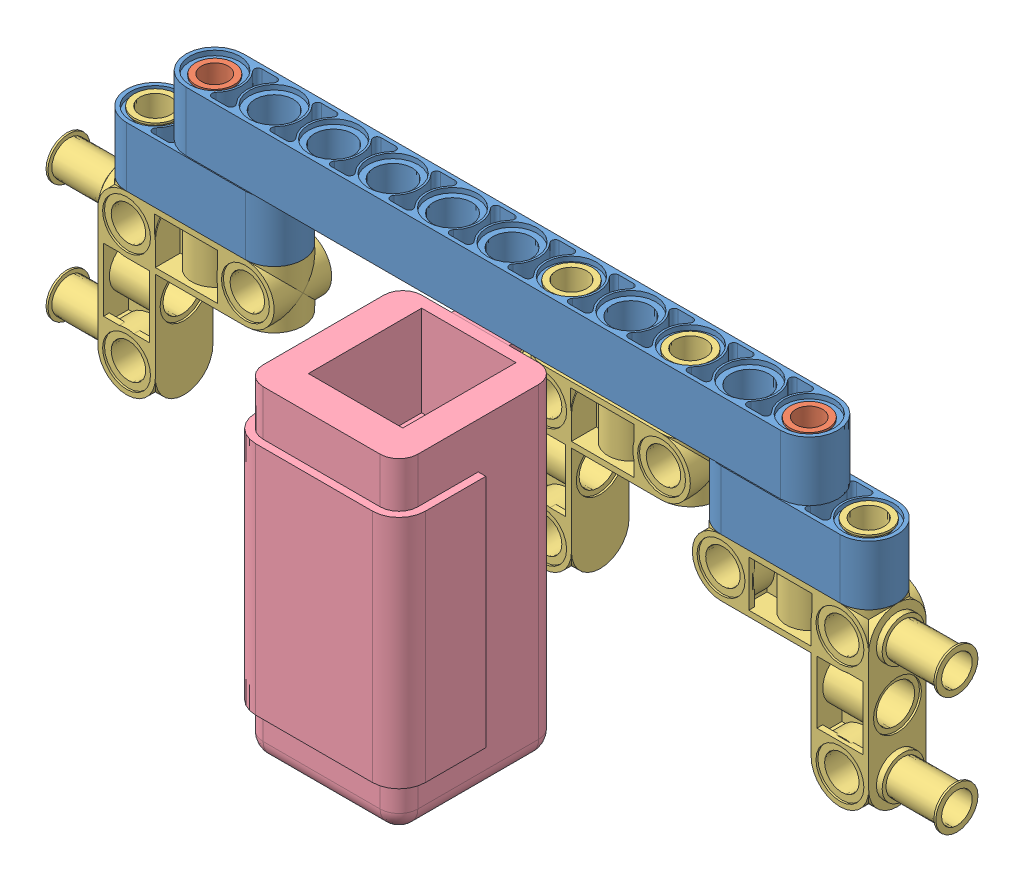
SolidWorks assembly lower_horizontal_connector, configuration Default. Lengths in mm.
Overall size (117.86 51.45 29.62).
9 component instances, 4 part files, 27 mates.
Components (placement in the parent):
- All_Straight-1: All_Straight [Eleven] x (1 0 0) z (0 1 0) size (86.36 7.62 7.87)
- BlueConnectorLong-1: BlueConnectorLong [Default] at (7.874 7.493 0) x (0 -1 0) z (0 0 1) size (22.86 5.59 5.59)
- BlueConnectorLong-2: BlueConnectorLong [Default] at (-70.866 7.493 0) x (0 -1 0) z (0 0 1) size (22.86 5.59 5.59)
- All_Straight-2: All_Straight [Three] at (7.874 -8.001 0) x (1 0 0) z (0 1 0) size (23.37 7.62 7.87)
- All_Straight-3: All_Straight [Three] at (-70.866 -8.001 0) x (1 0 0) z (0 1 0) size (23.37 7.62 7.87)
- Light_Gray_X10-1: Light_Gray_X10 [Default] at (-70.866 -15.621 0) size (31.24 31.24 7.62)
- Light_Gray_X10-3: Light_Gray_X10 [Default] at (7.874 -15.621 0) x (-1 0 0) z (0 0 -1) size (31.24 31.24 7.62)
- Light_Gray_X10-4: Light_Gray_X10 [Default] at (-15.748 -8.001 0) size (31.24 31.24 7.62)
- Light_sensor-1: Light_sensor [Default] at (-31.904 -21.981 14.31) x (-1 0 0) z (0 -1 0) size (22.5 29.62 43.2)
Mates (geometry in assembly coordinates):
- Coincident1: coincident aligned: plane of All_Straight-1 through (0 0 0) normal (0 1 0); plane of assembly through (0 0 0) normal (0 1 0)
- Coincident2: coincident aligned: plane of All_Straight-1; plane of assembly through (0 0 0) normal (1 0 0)
- Coincident3: coincident anti-aligned: plane of All_Straight-1 through (0 0 0) normal (0 0 -1); plane of assembly through (0 0 0) normal (0 0 1)
- Concentric1: concentric anti-aligned: cylinder of All_Straight-1 through (7.874 3.937 0) axis (0 -1 0) radius 2.54; cylinder of BlueConnectorLong-1 through (7.874 7.493 0) axis (0 1 0) radius 2.032
- Coincident4: coincident anti-aligned: plane of All_Straight-1 through (7.874 7.239 0) normal (0 1 0); plane of BlueConnectorLong-1 through (10.414 7.239 0) normal (0 -1 0)
- Parallel1: parallel aligned: plane of BlueConnectorLong-1; plane of assembly through (0 0 0) normal (1 0 0)
- Concentric2: concentric anti-aligned: cylinder of All_Straight-1 through (-70.866 3.937 0) axis (0 -1 0) radius 2.54; cylinder of BlueConnectorLong-2 through (-70.866 7.493 0) axis (0 1 0) radius 2.032
- Coincident5: coincident anti-aligned: plane of All_Straight-1 through (-70.866 7.239 0) normal (0 1 0); plane of BlueConnectorLong-2 through (-68.326 7.239 0) normal (0 -1 0)
- Parallel2: parallel aligned: plane of BlueConnectorLong-2; plane of assembly through (0 0 0) normal (1 0 0)
- Concentric3: concentric anti-aligned: cylinder of BlueConnectorLong-1 through (7.874 7.493 0) axis (0 1 0) radius 2.032; cylinder of All_Straight-2 through (7.874 -4.064 0) axis (0 -1 0) radius 2.54
- Coincident6: coincident anti-aligned: plane of BlueConnectorLong-1 through (9.906 -0.762 0) normal (0 -1 0); plane of All_Straight-2 through (7.874 -0.762 0) normal (0 1 0)
- Parallel3: parallel aligned: plane of All_Straight-1 through (0 3.937 3.81) normal (0 0 1); plane of All_Straight-2 through (7.874 -4.064 3.81) normal (0 0 1)
- Concentric4: concentric anti-aligned: cylinder of BlueConnectorLong-2 through (-70.866 7.493 0) axis (0 1 0) radius 2.032; cylinder of All_Straight-3 through (-70.866 -4.064 0) axis (0 -1 0) radius 2.54
- Coincident7: coincident anti-aligned: plane of BlueConnectorLong-2 through (-68.834 -0.762 0) normal (0 -1 0); plane of All_Straight-3 through (-70.866 -0.762 0) normal (0 1 0)
- Parallel4: parallel aligned: plane of All_Straight-1 through (0 3.937 3.81) normal (0 0 1); plane of All_Straight-3 through (-70.866 -4.064 3.81) normal (0 0 1)
- Concentric5: concentric aligned: cylinder of All_Straight-3 through (-62.992 -4.064 0) axis (0 -1 0) radius 2.54; cylinder of Light_Gray_X10-1 through (-62.992 -0.127 0) axis (0 -1 0) radius 2.286
- Concentric6: concentric aligned: cylinder of All_Straight-3 through (-78.74 -4.064 0) axis (0 -1 0) radius 2.54; cylinder of Light_Gray_X10-1 through (-78.74 -0.127 0) axis (0 -1 0) radius 2.286
- Concentric9: concentric aligned: cylinder of All_Straight-2 through (15.748 -4.064 0) axis (0 -1 0) radius 2.54; cylinder of Light_Gray_X10-3 through (15.748 -0.127 0) axis (0 -1 0) radius 2.286
- Concentric10: concentric aligned: cylinder of All_Straight-2 through (0 -4.064 0) axis (0 -1 0) radius 2.54; cylinder of Light_Gray_X10-3 through (0 -0.127 0) axis (0 -1 0) radius 2.286
- Coincident13: coincident aligned: plane of BlueConnectorLong-2 through (-68.326 -15.367 0) normal (0 -1 0); plane of Light_Gray_X10-1 through (-70.866 -15.367 0) normal (0 -1 0)
- Coincident14: coincident aligned: plane of BlueConnectorLong-1 through (10.414 -15.367 0) normal (0 -1 0); plane of Light_Gray_X10-3 through (7.874 -15.367 0) normal (0 -1 0)
- Concentric11: concentric aligned: cylinder of All_Straight-1 through (-23.622 3.937 0) axis (0 -1 0) radius 2.54; cylinder of Light_Gray_X10-4 through (-23.622 7.493 0) axis (0 -1 0) radius 2.286
- Concentric12: concentric aligned: cylinder of All_Straight-1 through (-7.874 3.937 0) axis (0 -1 0) radius 2.54; cylinder of Light_Gray_X10-4 through (-7.874 7.493 0) axis (0 -1 0) radius 2.286
- Coincident15: coincident anti-aligned: plane of All_Straight-1 through (-15.748 7.239 0) normal (0 1 0); plane of Light_Gray_X10-4 through (-23.622 7.239 0) normal (0 -1 0)
- Concentric13: concentric aligned: cylinder of Light_Gray_X10-4 through (-35.306 -4.191 0) axis (1 0 0) radius 2.286; cylinder of Light_sensor-1 through (-31.877 -4.191 0) axis (1 0 0) radius 2.54
- Concentric14: concentric aligned: cylinder of Light_Gray_X10-4 through (-35.306 -19.939 0) axis (1 0 0) radius 2.286; cylinder of Light_sensor-1 through (-31.877 -19.939 0) axis (1 0 0) radius 2.54
- Coincident16: coincident anti-aligned: plane of Light_Gray_X10-4 through (-35.052 -19.939 0) normal (1 0 0); plane of Light_sensor-1 through (-35.052 -19.939 0) normal (-1 0 0)
